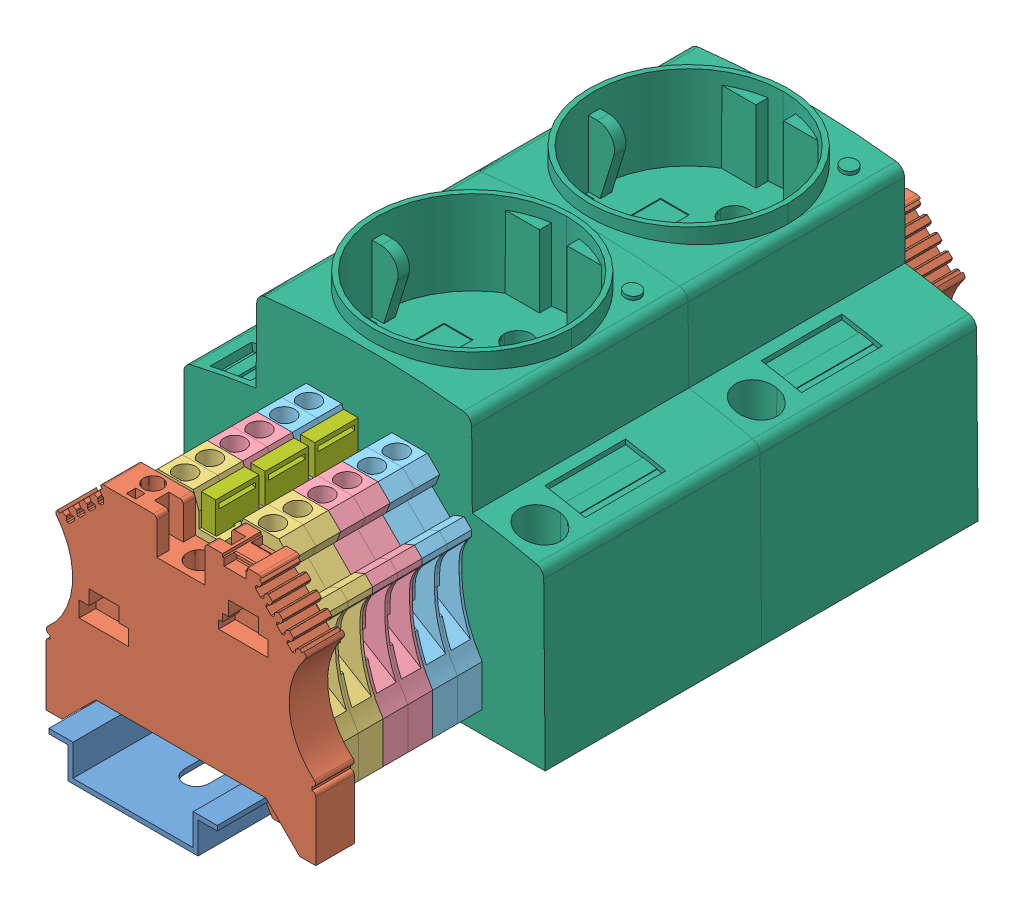
SolidWorks assembly Baugruppe5, configuration Standard. Lengths in mm.
Overall size (75.48 67.56 150).
14 component instances, 7 part files, 42 mates.
Components (placement in the parent):
- Hutschiene-1: Hutschiene [150] at (-17.5 -7.5 -150) size (35 7.5 150)
- WEW_35_2-1: WEW_35_2 [Standard] at (10.49 -7 -10) x (0 0 -1) z (0 1 0) size (8 56.1 46.5)
- UT_2.5-1: UT_2.5 [Standard] at (-48.9989 10.6178 -18) x (0.992546 -0.121869 0) z (0 0 1) size (49.27 50.96 5.15)
- UT_2.5-2: UT_2.5 [Standard] at (-48.9989 10.6178 -23.15) x (0.992546 -0.121869 0) z (0 0 1) size (49.27 50.96 5.15)
- UT_2.5_BU-1: UT_2.5_BU [Standard] at (-48.9989 10.6178 -28.3) x (0.992546 -0.121869 0) z (0 0 1) size (49.27 50.96 5.15)
- UT_2.5_BU-2: UT_2.5_BU [Standard] at (-48.9989 10.6178 -33.45) x (0.992546 -0.121869 0) z (0 0 1) size (49.27 50.96 5.15)
- UT_2.5_PE-1: UT_2.5_PE [Standard] at (-48.9989 10.6178 -38.6) x (0.992546 -0.121869 0) z (0 0 1) size (49.27 50.96 5.15)
- UT_2.5_PE-2: UT_2.5_PE [Standard] at (-48.9989 10.6178 -43.75) x (0.992546 -0.121869 0) z (0 0 1) size (49.27 50.96 5.15)
- EO_CF_UT_LED-1: EO_CF_UT_LED [Standard] at (-87.6914 -21.0563 -73.65) size (75.48 61.64 45)
- EO_CF_UT_LED-2: EO_CF_UT_LED [Standard] at (-87.6914 -21.0563 -118.65) size (75.48 61.64 45)
- FBS_2-5-2: FBS_2-5 [Standard] at (-24.4072 49.175 -76.835) size (3 22.98 9)
- FBS_2-5-3: FBS_2-5 [Standard] at (-24.4072 49.175 -87.135) size (3 22.98 9)
- FBS_2-5-1: FBS_2-5 [Standard] at (-24.4072 49.175 -97.435) size (3 22.98 9)
- WEW_35_2-3: WEW_35_2 [Standard] at (10.61 -7 -138.9) x (0 0 -1) z (0 1 0) size (8 56.1 46.5)
Mates (geometry in assembly coordinates):
- Deckungsgleich1: coincident aligned: plane of Hutschiene-1 through (-17.5 -7.5 0) normal (0 0 1); plane of assembly through (0 0 0) normal (0 0 1)
- Deckungsgleich2: coincident aligned: plane of Hutschiene-1 through (0 -1 0) normal (1 0 0); plane of assembly through (0 0 0) normal (1 0 0)
- Deckungsgleich3: coincident aligned: plane of Hutschiene-1 through (0 0 0) normal (0 1 0); plane of assembly through (0 0 0) normal (0 1 0)
- Deckungsgleich4: coincident anti-aligned: plane of Hutschiene-1 through (-30 0 0) normal (0 1 0); plane of WEW_35_2-1 through (-35.26 0 -33) normal (0 -1 0)
- Tangential1: tangent anti-aligned: cylinder of WEW_35_2-1 through (2 -1.4 -29) axis (0 0 -1) radius 2; plane of Hutschiene-1 through (0 -1 0) normal (1 0 0)
- Abstand1: distance = 10 mm aligned: plane of Hutschiene-1 through (-17.5 -7.5 0) normal (0 0 1); plane of WEW_35_2-1 through (-17.56 0 -10) normal (0 0 1)
- Deckungsgleich6: coincident anti-aligned: plane of WEW_35_2-1 through (-17.56 0 -33) normal (0 0 -1); plane of UT_2.5-1 through (-0.3 0 -33) normal (0 0 1)
- Deckungsgleich7: coincident anti-aligned: plane of UT_2.5-1 through (-0.3 0 -38.15) normal (0 0 -1); plane of UT_2.5-2 through (-0.3 0 -38.15) normal (0 0 1)
- Deckungsgleich8: coincident anti-aligned: plane of UT_2.5_BU-1 through (-0.3 0 -43.3) normal (0 0 1); plane of UT_2.5-2 through (-0.3 0 -43.3) normal (0 0 -1)
- Deckungsgleich9: coincident anti-aligned: plane of UT_2.5_BU-1 through (-0.3 0 -48.45) normal (0 0 -1); plane of UT_2.5_BU-2 through (-0.3 0 -48.45) normal (0 0 1)
- Deckungsgleich10: coincident anti-aligned: plane of UT_2.5_PE-1 through (-0.3 0 -53.6) normal (0 0 1); plane of UT_2.5_BU-2 through (-0.3 0 -53.6) normal (0 0 -1)
- Deckungsgleich11: coincident anti-aligned: plane of UT_2.5_PE-1 through (-0.3 0 -58.75) normal (0 0 -1); plane of UT_2.5_PE-2 through (-0.3 0 -58.75) normal (0 0 1)
- Deckungsgleich12: coincident anti-aligned: plane of EO_CF_UT_LED-1 through (-18.35 2.45 -63.9) normal (0 0 1); plane of UT_2.5_PE-2 through (-0.3 0 -63.9) normal (0 0 -1)
- Deckungsgleich13: coincident anti-aligned: plane of EO_CF_UT_LED-1 through (-18.35 2.45 -108.9) normal (0 0 -1); plane of EO_CF_UT_LED-2 through (-18.35 2.45 -108.9) normal (0 0 1)
- Deckungsgleich14: coincident anti-aligned: plane of EO_CF_UT_LED-2 through (-18.35 2.45 -153.9) normal (0 0 -1); plane of WEW_35_2-3 through (-17.44 0 -153.9) normal (0 0 1)
- Deckungsgleich15: coincident anti-aligned: plane of Hutschiene-1 through (-30 0 0) normal (0 1 0); plane of UT_2.5-1 through (-8 0 -33) normal (0 -1 0)
- Deckungsgleich16: coincident anti-aligned: plane of Hutschiene-1 through (-30 0 0) normal (0 1 0); plane of UT_2.5-2 through (-8 0 -38.15) normal (0 -1 0)
- Deckungsgleich17: coincident anti-aligned: plane of Hutschiene-1 through (-30 0 0) normal (0 1 0); plane of UT_2.5_BU-1 through (-8 0 -43.3) normal (0 -1 0)
- Deckungsgleich18: coincident anti-aligned: plane of Hutschiene-1 through (-30 0 0) normal (0 1 0); plane of UT_2.5_BU-2 through (-8 0 -48.45) normal (0 -1 0)
- Deckungsgleich19: coincident anti-aligned: plane of Hutschiene-1 through (-30 0 0) normal (0 1 0); plane of UT_2.5_PE-1 through (-8 0 -53.6) normal (0 -1 0)
- Deckungsgleich20: coincident anti-aligned: plane of Hutschiene-1 through (-30 0 0) normal (0 1 0); plane of UT_2.5_PE-2 through (-8 0 -58.75) normal (0 -1 0)
- Deckungsgleich21: coincident anti-aligned: plane of Hutschiene-1 through (-30 0 0) normal (0 1 0); plane of EO_CF_UT_LED-1 through (-54.65 0 -90.8) normal (0 -1 0)
- Deckungsgleich22: coincident anti-aligned: plane of Hutschiene-1 through (-30 0 0) normal (0 1 0); plane of EO_CF_UT_LED-2 through (-54.65 0 -135.8) normal (0 -1 0)
- Deckungsgleich23: coincident anti-aligned: plane of Hutschiene-1 through (-30 0 0) normal (0 1 0); plane of WEW_35_2-3 through (-35.14 0 -161.9) normal (0 -1 0)
- Deckungsgleich24: coincident anti-aligned: plane of Hutschiene-1 through (-35 0 0) normal (-1 0 0); plane of UT_2.5-1 through (-35 -0.3 -33) normal (1 0 0)
- Deckungsgleich25: coincident anti-aligned: plane of Hutschiene-1 through (-35 0 0) normal (-1 0 0); plane of UT_2.5-2 through (-35 -0.3 -38.15) normal (1 0 0)
- Deckungsgleich26: coincident anti-aligned: plane of Hutschiene-1 through (-35 0 0) normal (-1 0 0); plane of UT_2.5_BU-1 through (-35 -0.3 -43.3) normal (1 0 0)
- Deckungsgleich27: coincident anti-aligned: plane of Hutschiene-1 through (-35 0 0) normal (-1 0 0); plane of UT_2.5_BU-2 through (-35 -0.3 -48.45) normal (1 0 0)
- Deckungsgleich28: coincident anti-aligned: plane of Hutschiene-1 through (-35 0 0) normal (-1 0 0); plane of UT_2.5_PE-1 through (-35 -0.3 -53.6) normal (1 0 0)
- Deckungsgleich29: coincident anti-aligned: plane of Hutschiene-1 through (-35 0 0) normal (-1 0 0); plane of UT_2.5_PE-2 through (-35 -0.3 -58.75) normal (1 0 0)
- Deckungsgleich30: coincident anti-aligned: plane of Hutschiene-1 through (-35 0 0) normal (-1 0 0); plane of EO_CF_UT_LED-1 through (-35 -41.451 -95.15) normal (1 0 0)
- Deckungsgleich31: coincident anti-aligned: plane of Hutschiene-1 through (-35 0 0) normal (-1 0 0); plane of EO_CF_UT_LED-2 through (-35 -41.451 -140.15) normal (1 0 0)
- Tangential2: tangent anti-aligned: plane of Hutschiene-1 through (-35 0 0) normal (-1 0 0); cylinder of WEW_35_2-3 through (-37 -1.4 -157.9) axis (0 0 -1) radius 2
- Deckungsgleich32: coincident anti-aligned: plane of UT_2.5-1 through (-21.8 36.703 -33) normal (1 0 0); plane of FBS_2-5-2 through (-21.8 41.9423 -67.735) normal (-1 0 0)
- Deckungsgleich33: coincident anti-aligned: plane of UT_2.5-1 through (-18.65 21.85 -33.475) normal (0 0 -1); plane of FBS_2-5-2 through (-18.8 39.7 -33.475) normal (0 0 1)
- Deckungsgleich34: coincident aligned: plane of UT_2.5-1 through (-30.4 40 -33) normal (0 1 0); plane of FBS_2-5-2 through (-18.8 40 -12.975) normal (0 1 0)
- Deckungsgleich35: coincident aligned: plane of UT_2.5_BU-1 through (-30.4 40 -43.3) normal (0 1 0); plane of FBS_2-5-3 through (-18.8 40 -23.275) normal (0 1 0)
- Deckungsgleich36: coincident anti-aligned: plane of UT_2.5_BU-1 through (-18.65 21.85 -43.775) normal (0 0 -1); plane of FBS_2-5-3 through (-18.8 39.7 -43.775) normal (0 0 1)
- Deckungsgleich37: coincident anti-aligned: plane of UT_2.5_BU-1 through (-21.8 36.703 -43.3) normal (1 0 0); plane of FBS_2-5-3 through (-21.8 41.9423 -78.035) normal (-1 0 0)
- Deckungsgleich38: coincident aligned: plane of UT_2.5_PE-1 through (-30.4 40 -53.6) normal (0 1 0); plane of FBS_2-5-1 through (-18.8 40 -33.575) normal (0 1 0)
- Deckungsgleich39: coincident anti-aligned: plane of UT_2.5_PE-1 through (-18.65 21.85 -54.075) normal (0 0 -1); plane of FBS_2-5-1 through (-18.8 39.7 -54.075) normal (0 0 1)
- Deckungsgleich40: coincident anti-aligned: plane of UT_2.5_PE-1 through (-21.8 36.703 -53.6) normal (1 0 0); plane of FBS_2-5-1 through (-21.8 41.9423 -88.335) normal (-1 0 0)
